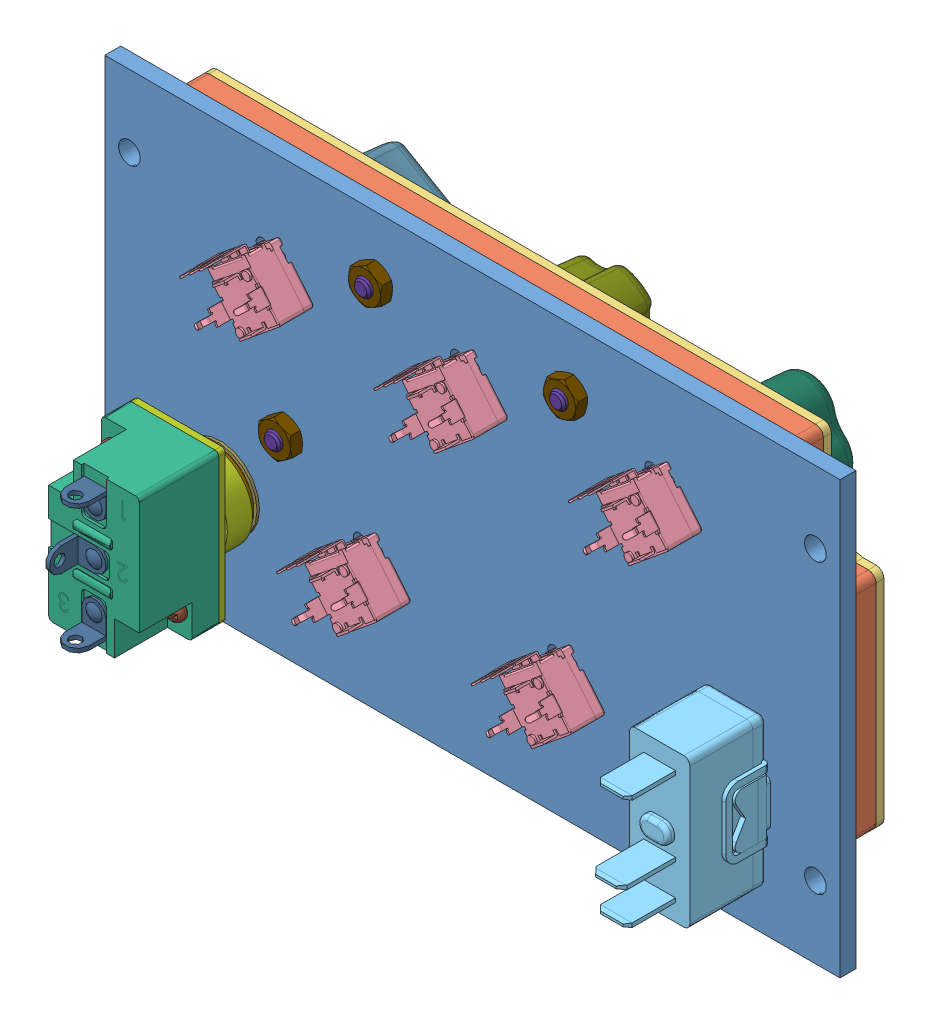
SolidWorks assembly INT LT Panel, configuration Default. Lengths in mm.
Overall size (187.9 176.76 67.95).
45 component instances, 22 part files, 68 mates.
Components (placement in the parent):
- INT Lights Backplate-1: INT Lights Backplate [Default] at origin size (146.05 85.72 3.17)
- INT Lights Lightplate-1: INT Lights Lightplate [Default] at (-62.6592 36.7702 -3.175) x (-0.412242 0.911074 0) z (0 0 -1) size (126.61 148.95 4.76)
- INT Lights Legend Plate-1: INT Lights Legend Plate [Default] at (-12.7329 -0.8336 -7.9375) x (-0.999979 0.006493 0) z (0 0 -1) size (144.73 84.92 1.59)
- P0915N-FC20BR10K-7: P0915N-FC20BR10K [Default] at (-33.782 64.135 0) x (0.77384 0.633381 0) z (0 0 -1) size (11.93 12.51 33.35)
- P0915N-FC20BR10K-2: P0915N-FC20BR10K [Default] at (-72.39 64.135 0) x (0.77384 0.633381 0) z (0 0 -1) size (11.93 12.51 33.35)
- P0915N-FC20BR10K-3: P0915N-FC20BR10K [Default] at (-110.998 64.135 0) x (0.77384 0.633381 0) z (0 0 -1) size (11.93 12.51 33.35)
- P0915N-FC20BR10K-6: P0915N-FC20BR10K [Default] at (-53.086 22.987 0) x (0.77384 0.633381 0) z (0 0 -1) size (11.93 12.51 33.35)
- P0915N-FC20BR10K-5: P0915N-FC20BR10K [Default] at (-91.694 22.987 0) x (0.77384 0.633381 0) z (0 0 -1) size (11.93 12.51 33.35)
- 635H_SLASH_2 - SWITCH, TOGGLE, ON-MOM, REGULAR BAT-1: 635H_SLASH_2 - SWITCH, TOGGLE, ON-MOM, REGULAR BAT [Default] at (-20.828 22.987 15) x (0 -1 0) z (1 0 0) size (29.5 54.47 14)
- SxAL-1: SxAL [S3AL - Tall Bat] at (-123.19 22.987 9.2202) x (-1 0 0) z (0 -1 0) size (18.01 67.95 30)
  - S2AL_SMC_body1-body-1: S2AL_SMC_body1-body [Default] at origin size (18.01 16.36 30)
  - S2AL_SMC_plate13-1: S2AL_SMC_plate13 [Default] at origin size (18.01 21.39 30)
  - S2AL_S2AL_bat-1: S2AL_S2AL_bat [Removed Bat] at (0 14.7066 0) size (7.39 24.87 7.39)
  - S2AL_AT537-1: S2AL_AT537 [Default] at (0 7.9629 0) x (1 0 0) z (0 -1 0) size (15.49 15.49 1.5)
  - S2AL_SMC_trmnls2-terminals-1: S2AL_SMC_trmnls2-terminals [Default] at (0 -15.0114 0) size (16.2 6.6 44.08)
  - S2AL_M2_5x7_5-1: S2AL_M2_5x7_5 [Default] at (6.4643 -5.2832 -10.541) x (1 0 0) z (0 -1 0) size (3.56 3.56 9.47)
  - S2AL_M2_5x7_5-2: S2AL_M2_5x7_5 [Default] at (-6.4643 -5.2832 10.541) x (1 0 0) z (0 -1 0) size (3.56 3.56 9.47)
  - S2AL_AT508-1: S2AL_AT508 [Default] at (0 8.9662 0) x (1 0 0) z (0 -1 0) size (15.8 15.8 0.51)
  - S2AL_AT503M-1: S2AL_AT503M [Default] at (0 12.0396 0) x (1 0 0) z (0 1 0) size (16 14 2.4)
  - Tall Locking Bat-1: Tall Locking Bat [Default] at origin size (10.87 21.06 10.87)
  - Conical Locking Bat-1: Conical Locking Bat [Default] x (0 0 -1) z (1 0 0) (suppressed, hidden)
  - Round Locking Bat-1: Round Locking Bat [Default] x (0 0 -1) z (1 0 0) (suppressed, hidden)
- MS21385-04CNN v1-1: MS21385-04CNN v1 [Default] at (-110.998 64.135 -9.525) x (-0.5 -0.866025 0) z (0 0 -1) size (22.35 22.35 19.07)
- MS21385-04CNN v1-2: MS21385-04CNN v1 [Default] at (-53.086 22.987 -9.525) x (-0.5 -0.866025 0) z (0 0 -1) size (22.35 22.35 19.07)
- MS21385-04ENN v3-1: MS21385-04ENN v3 [Default] at (-92.0014 23.5195 -8.7236) x (-0.5 -0.866025 0) z (0 0 -1) size (22.23 22.23 19.09)
- MS21385-04ENN v3-2: MS21385-04ENN v3 [Default] at (-33.782 64.135 -9.525) x (-0.5 -0.866025 0) z (0 0 -1) size (22.23 22.23 19.09)
- MS21385-04BNN v1-1: MS21385-04BNN v1 [Default] at (-72.39 64.135 -9.525) x (-0.5 -0.866025 0) z (0 0 -1) size (22.35 22.35 19.07)
- 91249A148 - PHS, 6-32 X .500, 18-8, BLACK-OXIDE-1: 91249A148 - PHS, 6-32 X .500, 18-8, BLACK-OXIDE [91249A148] at (-53.34 74.041 3.175) x (-0.593348 -0.804946 0) z (0 0 -1) size (6.86 6.86 15.21)
- 90760A007 - NUT, 6-32, JAM, STEEL, ZINC-PLATED-1: 90760A007 - NUT, 6-32, JAM, STEEL, ZINC-PLATED [90760A007] at (-53.34 74.041 1.1906) x (0.322536 -0.946557 0) z (-0.946557 -0.322536 0) size (6.35 2.99 7.33)
- 90760A007 - NUT, 6-32, JAM, STEEL, ZINC-PLATED-2: 90760A007 - NUT, 6-32, JAM, STEEL, ZINC-PLATED [90760A007] at (-92.075 74.041 1.1906) x (0.468535 -0.883445 0) z (-0.883445 -0.468535 0) size (6.35 2.99 7.33)
- 91249A148 - PHS, 6-32 X .500, 18-8, BLACK-OXIDE-2: 91249A148 - PHS, 6-32 X .500, 18-8, BLACK-OXIDE [91249A148] at (-92.075 74.041 3.175) x (-0.458216 -0.888841 0) z (0 0 -1) size (6.86 6.86 15.21)
- 90760A007 - NUT, 6-32, JAM, STEEL, ZINC-PLATED-3: 90760A007 - NUT, 6-32, JAM, STEEL, ZINC-PLATED [90760A007] at (-109.982 38.735 1.1906) x (0.577213 -0.816594 0) z (-0.816594 -0.577213 0) size (6.35 2.99 7.33)
- 91249A148 - PHS, 6-32 X .500, 18-8, BLACK-OXIDE-3: 91249A148 - PHS, 6-32 X .500, 18-8, BLACK-OXIDE [91249A148] at (-109.982 38.735 3.175) x (-0.341308 -0.939951 0) z (0 0 -1) size (6.86 6.86 15.21)
- 90760A007 - NUT, 6-32, JAM, STEEL, ZINC-PLATED-4: 90760A007 - NUT, 6-32, JAM, STEEL, ZINC-PLATED [90760A007] at (-33.528 13.589 1.1906) x (0.650816 -0.759235 0) z (-0.759235 -0.650816 0) size (6.35 2.99 7.33)
- 91249A148 - PHS, 6-32 X .500, 18-8, BLACK-OXIDE-4: 91249A148 - PHS, 6-32 X .500, 18-8, BLACK-OXIDE [91249A148] at (-33.528 13.589 3.175) x (-0.252207 -0.967673 0) z (0 0 -1) size (6.86 6.86 15.21)
- 92311A189 - SCREW, SET, 8-32 X .1875, CUP POINT, HEX DRIVE, 18-8-2: 92311A189 - SCREW, SET, 8-32 X .1875, CUP POINT, HEX DRIVE, 18-8 [92311A189] at (-96.9587 20.6574 -16.5976) x (0.182145 -0.315485 -0.931285) z (-0.866025 -0.5 0) size (4.2 4.28 5.07)
- 92311A189 - SCREW, SET, 8-32 X .1875, CUP POINT, HEX DRIVE, 18-8-3: 92311A189 - SCREW, SET, 8-32 X .1875, CUP POINT, HEX DRIVE, 18-8 [92311A189] at (-92.0014 28.7111 -16.5976) x (-0.920412 0 -0.39095) z (0 1 0) size (4.2 4.28 5.07)
- 92311A189 - SCREW, SET, 8-32 X .1875, CUP POINT, HEX DRIVE, 18-8-5: 92311A189 - SCREW, SET, 8-32 X .1875, CUP POINT, HEX DRIVE, 18-8 [92311A189] at (-58.0432 25.8491 -17.399) x (0.31716 0.549337 0.773071) z (-0.866025 0.5 0) size (4.2 4.28 5.07)
- 92311A189 - SCREW, SET, 8-32 X .1875, CUP POINT, HEX DRIVE, 18-8-6: 92311A189 - SCREW, SET, 8-32 X .1875, CUP POINT, HEX DRIVE, 18-8 [92311A189] at (-50.2239 27.9442 -17.399) x (-0.512508 0.295897 -0.806089) z (0.5 0.866025 0) size (4.2 4.28 5.07)
- 92311A189 - SCREW, SET, 8-32 X .1875, CUP POINT, HEX DRIVE, 18-8-8: 92311A189 - SCREW, SET, 8-32 X .1875, CUP POINT, HEX DRIVE, 18-8 [92311A189] at (-115.9552 66.9971 -17.399) x (0.487367 0.844145 -0.223367) z (-0.866025 0.5 0) size (4.2 4.28 5.07)
- 92311A189 - SCREW, SET, 8-32 X .1875, CUP POINT, HEX DRIVE, 18-8-9: 92311A189 - SCREW, SET, 8-32 X .1875, CUP POINT, HEX DRIVE, 18-8 [92311A189] at (-108.1359 69.0922 -17.399) x (-0.662727 0.382625 -0.643732) z (0.5 0.866025 0) size (4.2 4.28 5.07)
- 92311A189 - SCREW, SET, 8-32 X .1875, CUP POINT, HEX DRIVE, 18-8-10: 92311A189 - SCREW, SET, 8-32 X .1875, CUP POINT, HEX DRIVE, 18-8 [92311A189] at (-73.8715 69.6641 -17.399) x (-0.954084 -0.255646 0.156108) z (-0.258819 0.965926 0) size (4.2 4.28 5.07)
- 92311A189 - SCREW, SET, 8-32 X .1875, CUP POINT, HEX DRIVE, 18-8-11: 92311A189 - SCREW, SET, 8-32 X .1875, CUP POINT, HEX DRIVE, 18-8 [92311A189] at (-77.9191 62.6535 -17.399) x (0.151193 -0.564261 -0.811634) z (-0.965926 -0.258819 0) size (4.2 4.28 5.07)
- 92311A189 - SCREW, SET, 8-32 X .1875, CUP POINT, HEX DRIVE, 18-8-12: 92311A189 - SCREW, SET, 8-32 X .1875, CUP POINT, HEX DRIVE, 18-8 [92311A189] at (-38.7392 61.2729 -17.399) x (0.073403 -0.127137 -0.989165) z (-0.866025 -0.5 0) size (4.2 4.28 5.07)
- 92311A189 - SCREW, SET, 8-32 X .1875, CUP POINT, HEX DRIVE, 18-8-13: 92311A189 - SCREW, SET, 8-32 X .1875, CUP POINT, HEX DRIVE, 18-8 [92311A189] at (-33.782 69.8591 -17.399) x (-0.768667 0 0.639649) z (0 1 0) size (4.2 4.28 5.07)
Mates (geometry in assembly coordinates):
- Concentric47: concentric aligned: cylinder of INT Lights Backplate-1 through (-20.828 22.987 0) axis (0 0 -1) radius 6.35; cone of 635H_SLASH_2 - SWITCH, TOGGLE, ON-MOM, REGULAR BAT-1 through (-20.828 22.987 -9.7795) axis (0 0 -1)
- Coincident89: coincident anti-aligned: plane of INT Lights Backplate-1 through (0 0 0) normal (0 0 1); plane of 635H_SLASH_2 - SWITCH, TOGGLE, ON-MOM, REGULAR BAT-1 through (-20.828 22.987 0) normal (0 0 -1)
- Parallel10: parallel anti-aligned: plane of INT Lights Backplate-1 through (0 0 -3.175) normal (1 0 0); plane of 635H_SLASH_2 - SWITCH, TOGGLE, ON-MOM, REGULAR BAT-1 through (-14.828 36.537 15) normal (-1 0 0)
- Concentric48: concentric aligned: cylinder of INT Lights Backplate-1 through (-123.19 22.987 0) axis (0 0 -1) radius 6.35; cylinder of SxAL-1/S2AL_SMC_plate13-1 through (-123.19 22.987 8.2804) axis (0 0 -1) radius 8.4963
- Coincident90: coincident anti-aligned: plane of INT Lights Backplate-1 through (0 0 0) normal (0 0 1); plane of SxAL-1/S2AL_AT508-1 through (-123.19 22.987 0) normal (0 0 -1)
- Parallel11: parallel anti-aligned: plane of INT Lights Backplate-1 through (-146.05 85.725 -3.175) normal (-1 0 0); plane of SxAL-1/S2AL_SMC_body1-body-1 through (-114.1857 37.2237 25.019) normal (1 0 0)
- Coincident91: coincident anti-aligned: plane of INT Lights Lightplate-1 through (-141.1605 71.4375 -3.175) normal (0 0 1); plane of INT Lights Backplate-1 through (0 0 -3.175) normal (0 0 -1)
- Width1: width anti-aligned: plane of INT Lights Backplate-1 through (0 0 -3.175) normal (1 0 0); plane of INT Lights Backplate-1 through (-146.05 85.725 -3.175) normal (-1 0 0); plane of INT Lights Lightplate-1 through (-145.2562 22.1615 -7.9375) normal (-1 0 0); plane of INT Lights Lightplate-1 through (-0.7937 63.5635 -7.9375) normal (1 0 0)
- Width2: width anti-aligned: plane of INT Lights Lightplate-1 through (-12.7635 0.7937 -7.9375) normal (0 -1 0); plane of INT Lights Lightplate-1 through (-133.2865 84.9313 -7.9375) normal (0 1 0); plane of INT Lights Backplate-1 through (0 85.725 -3.175) normal (0 1 0); plane of INT Lights Backplate-1 through (-146.05 0 -3.175) normal (0 -1 0)
- Coincident92: coincident aligned: plane of INT Lights Lightplate-1 through (-145.2562 22.1615 -7.9375) normal (-1 0 0); plane of INT Lights Legend Plate-1 through (-145.2562 22.1615 -9.525) normal (-1 0 0)
- Coincident93: coincident aligned: plane of INT Lights Lightplate-1 through (-12.7635 0.7937 -7.9375) normal (0 -1 0); plane of INT Lights Legend Plate-1 through (-12.7635 0.7937 -9.525) normal (0 -1 0)
- Concentric51: concentric aligned: cylinder of P0915N-FC20BR10K-3 through (-110.998 64.135 0) axis (0 0 -1) radius 3; cylinder of MS21385-04CNN v1-1 through (-110.998 64.135 -9.525) axis (0 0 -1) radius 86.4507
- Parallel14: parallel anti-aligned: plane of P0915N-FC20BR10K-3 through (-108.3999 65.635 -12.7) normal (0.866025 -0.5 0); plane of MS21385-04CNN v1-1 through (-107.8365 64.7086 -9.525) normal (-0.866025 0.5 0)
- Coincident96: coincident anti-aligned: plane of INT Lights Legend Plate-1 through (-141.1605 71.4375 -9.525) normal (0 0 -1); plane of MS21385-04CNN v1-1 through (-116.586 54.4563 -9.525) normal (0 0 1)
- Concentric52: concentric aligned: cylinder of P0915N-FC20BR10K-6 through (-53.086 22.987 0) axis (0 0 -1) radius 3; cylinder of MS21385-04CNN v1-2 through (-53.086 22.987 -9.525) axis (0 0 -1) radius 86.4507
- Parallel15: parallel anti-aligned: plane of P0915N-FC20BR10K-6 through (-50.4879 24.487 -12.7) normal (0.866025 -0.5 0); plane of MS21385-04CNN v1-2 through (-49.9245 23.5606 -9.525) normal (-0.866025 0.5 0)
- Coincident97: coincident anti-aligned: plane of INT Lights Legend Plate-1 through (-141.1605 71.4375 -9.525) normal (0 0 -1); plane of MS21385-04CNN v1-2 through (-58.674 13.3083 -9.525) normal (0 0 1)
- Concentric54: concentric anti-aligned: cylinder of INT Lights Backplate-1 through (-53.34 74.041 -3.175) axis (0 0 -1) radius 2.1526; cylinder of 91249A148 - PHS, 6-32 X .500, 18-8, BLACK-OXIDE-1 through (-53.34 74.041 3.175) axis (0 0 1) radius 3.429
- Coincident99: coincident anti-aligned: plane of INT Lights Legend Plate-1 through (-141.1605 71.4375 -9.525) normal (0 0 -1); plane of 91249A148 - PHS, 6-32 X .500, 18-8, BLACK-OXIDE-1 through (-53.34 74.041 -9.525) normal (0 0 1)
- Concentric55: concentric aligned: cylinder of 91249A148 - PHS, 6-32 X .500, 18-8, BLACK-OXIDE-1 through (-53.34 74.041 3.175) axis (0 0 1) radius 3.429; circle of 90760A007 - NUT, 6-32, JAM, STEEL, ZINC-PLATED-1
- Coincident100: coincident anti-aligned: plane of INT Lights Backplate-1 through (0 0 0) normal (0 0 1); plane of 90760A007 - NUT, 6-32, JAM, STEEL, ZINC-PLATED-1 through (-52.6289 77.6376 0) normal (0 0 -1)
- Concentric56: concentric aligned: circle of 90760A007 - NUT, 6-32, JAM, STEEL, ZINC-PLATED-2; cylinder of 91249A148 - PHS, 6-32 X .500, 18-8, BLACK-OXIDE-2 through (-92.075 74.041 3.175) axis (0 0 1) radius 3.429
- Coincident101: coincident anti-aligned: plane of INT Lights Legend Plate-1 through (-141.1605 71.4375 -9.525) normal (0 0 -1); plane of 91249A148 - PHS, 6-32 X .500, 18-8, BLACK-OXIDE-2 through (-92.075 74.041 -9.525) normal (0 0 1)
- Coincident102: coincident anti-aligned: plane of INT Lights Backplate-1 through (0 0 0) normal (0 0 1); plane of 90760A007 - NUT, 6-32, JAM, STEEL, ZINC-PLATED-2 through (-91.9432 77.7048 0) normal (0 0 -1)
- Concentric57: concentric anti-aligned: cylinder of INT Lights Backplate-1 through (-92.075 74.041 -3.175) axis (0 0 -1) radius 2.1526; cylinder of 91249A148 - PHS, 6-32 X .500, 18-8, BLACK-OXIDE-2 through (-92.075 74.041 3.175) axis (0 0 1) radius 3.429
- Concentric58: concentric aligned: circle of 90760A007 - NUT, 6-32, JAM, STEEL, ZINC-PLATED-3; cylinder of 91249A148 - PHS, 6-32 X .500, 18-8, BLACK-OXIDE-3 through (-109.982 38.735 3.175) axis (0 0 1) radius 3.429
- Coincident103: coincident anti-aligned: plane of INT Lights Legend Plate-1 through (-141.1605 71.4375 -9.525) normal (0 0 -1); plane of 91249A148 - PHS, 6-32 X .500, 18-8, BLACK-OXIDE-3 through (-109.982 38.735 -9.525) normal (0 0 1)
- Coincident104: coincident anti-aligned: plane of INT Lights Backplate-1 through (0 0 0) normal (0 0 1); plane of 90760A007 - NUT, 6-32, JAM, STEEL, ZINC-PLATED-3 through (-110.3178 42.3858 0) normal (0 0 -1)
- Concentric59: concentric anti-aligned: cylinder of INT Lights Backplate-1 through (-109.982 38.735 -3.175) axis (0 0 -1) radius 2.1526; cylinder of 91249A148 - PHS, 6-32 X .500, 18-8, BLACK-OXIDE-3 through (-109.982 38.735 3.175) axis (0 0 1) radius 3.429
- Concentric60: concentric aligned: circle of 90760A007 - NUT, 6-32, JAM, STEEL, ZINC-PLATED-4; cylinder of 91249A148 - PHS, 6-32 X .500, 18-8, BLACK-OXIDE-4 through (-33.528 13.589 3.175) axis (0 0 1) radius 3.429
- Coincident105: coincident anti-aligned: plane of INT Lights Legend Plate-1 through (-141.1605 71.4375 -9.525) normal (0 0 -1); plane of 91249A148 - PHS, 6-32 X .500, 18-8, BLACK-OXIDE-4 through (-33.528 13.589 -9.525) normal (0 0 1)
- Coincident106: coincident anti-aligned: plane of INT Lights Backplate-1 through (0 0 0) normal (0 0 1); plane of 90760A007 - NUT, 6-32, JAM, STEEL, ZINC-PLATED-4 through (-34.2026 17.1926 0) normal (0 0 -1)
- Concentric61: concentric anti-aligned: cylinder of INT Lights Backplate-1 through (-33.528 13.589 -3.175) axis (0 0 -1) radius 2.1526; cylinder of 91249A148 - PHS, 6-32 X .500, 18-8, BLACK-OXIDE-4 through (-33.528 13.589 3.175) axis (0 0 1) radius 3.429
- Angle6: planar angle = 1.932079 rad anti-aligned: plane of P0915N-FC20BR10K-7 through (-27.8013 75.7188 -8) normal (0.935444 -0.353475 0); plane of INT Lights Backplate-1 through (-146.05 0 -3.175) normal (0 -1 0)
- Concentric62: concentric aligned: cylinder of INT Lights Backplate-1 through (-33.782 64.135 0) axis (0 0 -1) radius 3.7703; cylinder of P0915N-FC20BR10K-7 through (-33.782 64.135 -5) axis (0 0 -1) radius 3
- Coincident107: coincident anti-aligned: plane of INT Lights Backplate-1 through (0 0 0) normal (0 0 1); plane of P0915N-FC20BR10K-7 through (-33.782 64.135 0) normal (0 0 -1)
- Parallel17: parallel aligned: plane of P0915N-FC20BR10K-7 through (-27.8013 75.7188 -8) normal (0.935444 -0.353475 0); plane of P0915N-FC20BR10K-2 through (-66.4093 75.7188 -8) normal (0.935444 -0.353475 0)
- Parallel18: parallel aligned: plane of P0915N-FC20BR10K-7 through (-27.8013 75.7188 -8) normal (0.935444 -0.353475 0); plane of P0915N-FC20BR10K-3 through (-105.0173 75.7188 -8) normal (0.935444 -0.353475 0)
- Parallel19: parallel aligned: plane of P0915N-FC20BR10K-7 through (-27.8013 75.7188 -8) normal (0.935444 -0.353475 0); plane of P0915N-FC20BR10K-5 through (-85.7133 34.5708 -8) normal (0.935444 -0.353475 0)
- Parallel20: parallel aligned: plane of P0915N-FC20BR10K-7 through (-27.8013 75.7188 -8) normal (0.935444 -0.353475 0); plane of P0915N-FC20BR10K-6 through (-47.1053 34.5708 -8) normal (0.935444 -0.353475 0)
- Concentric63: concentric aligned: cylinder of INT Lights Backplate-1 through (-72.39 64.135 0) axis (0 0 -1) radius 3.7703; cylinder of P0915N-FC20BR10K-2 through (-72.39 64.135 -5) axis (0 0 -1) radius 3
- Coincident108: coincident anti-aligned: plane of INT Lights Backplate-1 through (0 0 0) normal (0 0 1); plane of P0915N-FC20BR10K-2 through (-72.39 64.135 0) normal (0 0 -1)
- Concentric64: concentric aligned: cylinder of INT Lights Backplate-1 through (-110.998 64.135 0) axis (0 0 -1) radius 3.7703; cylinder of P0915N-FC20BR10K-3 through (-110.998 64.135 -5) axis (0 0 -1) radius 3
- Coincident109: coincident aligned: plane of P0915N-FC20BR10K-2 through (-72.39 64.135 -20) normal (0 0 -1); plane of P0915N-FC20BR10K-3 through (-110.998 64.135 -20) normal (0 0 -1)
- Concentric65: concentric aligned: cylinder of INT Lights Backplate-1 through (-91.694 22.987 0) axis (0 0 -1) radius 3.7703; cylinder of P0915N-FC20BR10K-5 through (-91.694 22.987 -5) axis (0 0 -1) radius 3
- Coincident110: coincident aligned: plane of P0915N-FC20BR10K-3 through (-110.998 64.135 -20) normal (0 0 -1); plane of P0915N-FC20BR10K-5 through (-91.694 22.987 -20) normal (0 0 -1)
- Concentric66: concentric aligned: cylinder of INT Lights Backplate-1 through (-53.086 22.987 0) axis (0 0 -1) radius 3.7703; cylinder of P0915N-FC20BR10K-6 through (-53.086 22.987 -5) axis (0 0 -1) radius 3
- Coincident111: coincident aligned: plane of P0915N-FC20BR10K-6 through (-53.086 22.987 -20) normal (0 0 -1); plane of P0915N-FC20BR10K-5 through (-91.694 22.987 -20) normal (0 0 -1)
- Concentric67: concentric aligned: cylinder of MS21385-04ENN v3-1 through (-92.0014 23.5195 -16.5976) axis (-0.866025 -0.5 0) radius 2.0828; cone of 92311A189 - SCREW, SET, 8-32 X .1875, CUP POINT, HEX DRIVE, 18-8-2 through (-95.1934 21.6766 -16.5976) axis (-0.866025 -0.5 0)
- Tangent2: tangent: cylinder of P0915N-FC20BR10K-5 through (-91.694 22.987 -5) axis (0 0 -1) radius 3; circle of 92311A189 - SCREW, SET, 8-32 X .1875, CUP POINT, HEX DRIVE, 18-8-2
- Concentric68: concentric aligned: cylinder of MS21385-04ENN v3-1 through (-92.0014 23.5195 -16.5976) axis (0 1 0) radius 2.0828; cone of 92311A189 - SCREW, SET, 8-32 X .1875, CUP POINT, HEX DRIVE, 18-8-3 through (-92.0014 26.6728 -16.5976) axis (0 1 0)
- Tangent3: tangent: cylinder of P0915N-FC20BR10K-5 through (-91.694 22.987 -5) axis (0 0 -1) radius 3; circle of 92311A189 - SCREW, SET, 8-32 X .1875, CUP POINT, HEX DRIVE, 18-8-3
- Concentric70: concentric aligned: cylinder of MS21385-04CNN v1-2 through (-53.086 22.987 -17.399) axis (-0.866025 0.5 0) radius 2.0828; cone of 92311A189 - SCREW, SET, 8-32 X .1875, CUP POINT, HEX DRIVE, 18-8-5 through (-56.278 24.8299 -17.399) axis (-0.866025 0.5 0)
- Tangent4: tangent: cylinder of P0915N-FC20BR10K-6 through (-53.086 22.987 -5) axis (0 0 -1) radius 3; circle of 92311A189 - SCREW, SET, 8-32 X .1875, CUP POINT, HEX DRIVE, 18-8-5
- Concentric71: concentric anti-aligned: cylinder of MS21385-04CNN v1-2 through (-53.086 22.987 -17.399) axis (0.5 0.866025 0) radius 1.7082; cone of 92311A189 - SCREW, SET, 8-32 X .1875, CUP POINT, HEX DRIVE, 18-8-6 through (-51.586 25.5851 -17.399) axis (-0.5 -0.866025 0)
- Tangent5: tangent: cylinder of P0915N-FC20BR10K-6 through (-53.086 22.987 -5) axis (0 0 -1) radius 3; circle of 92311A189 - SCREW, SET, 8-32 X .1875, CUP POINT, HEX DRIVE, 18-8-6
- Concentric72: concentric anti-aligned: cylinder of MS21385-04CNN v1-1 through (-110.998 64.135 -17.399) axis (-0.866025 0.5 0) radius 2.0828; cone of 92311A189 - SCREW, SET, 8-32 X .1875, CUP POINT, HEX DRIVE, 18-8-8 through (-113.5961 65.635 -17.399) axis (0.866025 -0.5 0)
- Tangent6: tangent: cylinder of P0915N-FC20BR10K-3 through (-110.998 64.135 -5) axis (0 0 -1) radius 3; circle of 92311A189 - SCREW, SET, 8-32 X .1875, CUP POINT, HEX DRIVE, 18-8-8
- Concentric73: concentric anti-aligned: cylinder of MS21385-04CNN v1-1 through (-110.998 64.135 -17.399) axis (0.5 0.866025 0) radius 2.0828; cone of 92311A189 - SCREW, SET, 8-32 X .1875, CUP POINT, HEX DRIVE, 18-8-9 through (-109.498 66.7331 -17.399) axis (-0.5 -0.866025 0)
- Tangent7: tangent: cylinder of P0915N-FC20BR10K-3 through (-110.998 64.135 -5) axis (0 0 -1) radius 3; circle of 92311A189 - SCREW, SET, 8-32 X .1875, CUP POINT, HEX DRIVE, 18-8-9
- Concentric74: concentric anti-aligned: cylinder of MS21385-04BNN v1-1 through (-72.39 64.135 -17.399) axis (-0.258819 0.965926 0) radius 1.7082; cone of 92311A189 - SCREW, SET, 8-32 X .1875, CUP POINT, HEX DRIVE, 18-8-10 through (-73.1665 67.0328 -17.399) axis (0.258819 -0.965926 0)
- Tangent8: tangent: cylinder of P0915N-FC20BR10K-2 through (-72.39 64.135 -5) axis (0 0 -1) radius 3; circle of 92311A189 - SCREW, SET, 8-32 X .1875, CUP POINT, HEX DRIVE, 18-8-10
- Concentric75: concentric anti-aligned: cylinder of MS21385-04BNN v1-1 through (-72.39 64.135 -17.399) axis (-0.965926 -0.258819 0) radius 1.7082; cone of 92311A189 - SCREW, SET, 8-32 X .1875, CUP POINT, HEX DRIVE, 18-8-11 through (-75.2878 63.3585 -17.399) axis (0.965926 0.258819 0)
- Tangent9: tangent: cylinder of P0915N-FC20BR10K-2 through (-72.39 64.135 -5) axis (0 0 -1) radius 3; circle of 92311A189 - SCREW, SET, 8-32 X .1875, CUP POINT, HEX DRIVE, 18-8-11
- Concentric76: concentric anti-aligned: cylinder of MS21385-04ENN v3-2 through (-33.782 64.135 -17.399) axis (-0.866025 -0.5 0) radius 2.0828; cylinder of 92311A189 - SCREW, SET, 8-32 X .1875, CUP POINT, HEX DRIVE, 18-8-12 through (-36.3801 62.635 -17.399) axis (0.866025 0.5 0) radius 785.3982
- Tangent10: tangent: cylinder of P0915N-FC20BR10K-7 through (-33.782 64.135 -5) axis (0 0 -1) radius 3; circle of 92311A189 - SCREW, SET, 8-32 X .1875, CUP POINT, HEX DRIVE, 18-8-12
- Concentric77: concentric anti-aligned: cylinder of MS21385-04ENN v3-2 through (-33.782 64.135 -17.399) axis (0 1 0) radius 2.0828; cone of 92311A189 - SCREW, SET, 8-32 X .1875, CUP POINT, HEX DRIVE, 18-8-13 through (-33.782 67.135 -17.399) axis (0 -1 0)
- Tangent11: tangent: cylinder of P0915N-FC20BR10K-7 through (-33.782 64.135 -5) axis (0 0 -1) radius 3; circle of 92311A189 - SCREW, SET, 8-32 X .1875, CUP POINT, HEX DRIVE, 18-8-13
